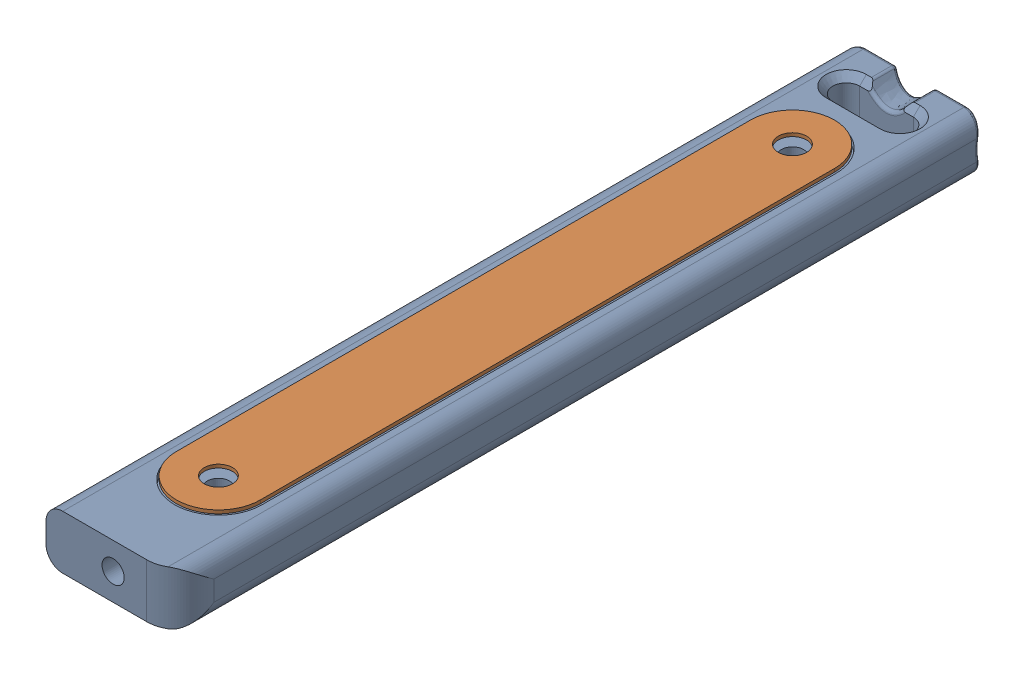
SolidWorks assembly Ruler_asm, configuration 預設. Lengths in mm.
Overall size (20 8.04 119.86).
2 component instances, 2 part files, 2 mates.
Components (placement in the parent):
- Ruler_Basic_Template-1: Ruler_Basic_Template [預設] at origin size (20 8.04 119.86)
- stainless_Nameplate_template-1: stainless_Nameplate_template [預設] at (-0.002 8 1.5716) x (0 0 -1) z (1 0 0) size (98 0.5 12.5) (hidden)
Mates (geometry in assembly coordinates):
- 重合/共線/共點4: coincident anti-aligned: plane of Ruler_Basic_Template-1 through (0 8 0) normal (0 1 0); plane of stainless_Nameplate_template-1 through (-0.002 8 44.3216) normal (0 -1 0)
- 平行2: parallel anti-aligned: plane of Ruler_Basic_Template-1 through (-10 8 -60) normal (-1 0 0); plane of stainless_Nameplate_template-1 through (6.248 8.5 44.3216) normal (1 0 0)
